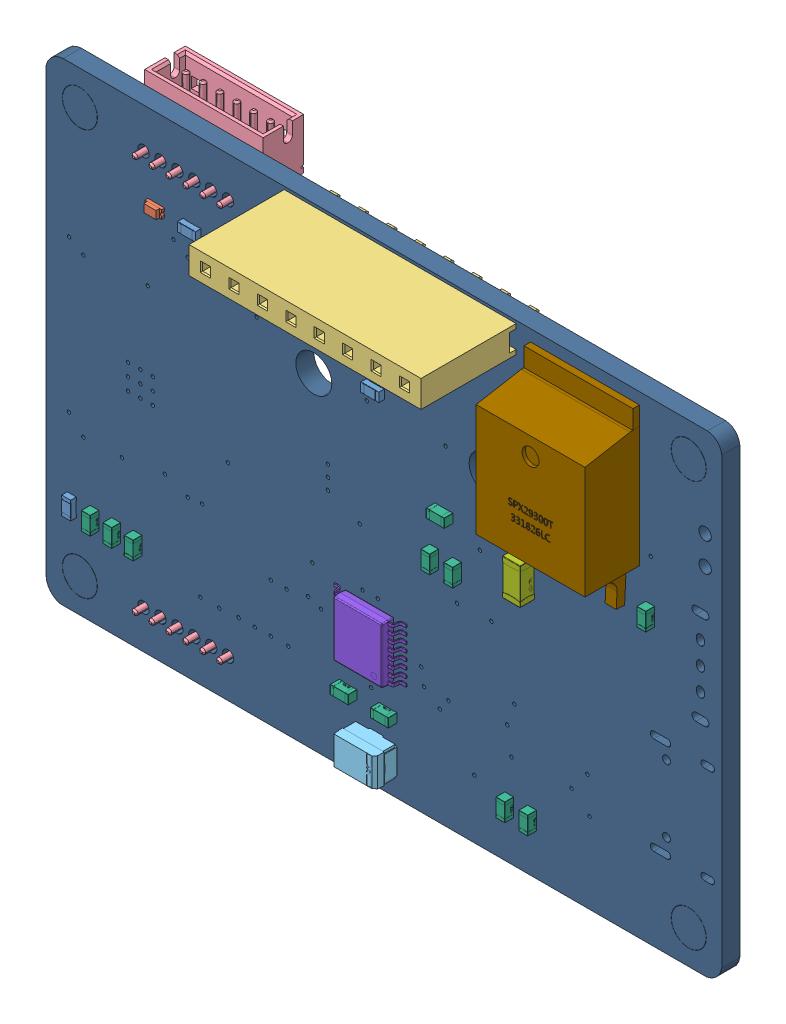
SolidWorks assembly 3D_PCB, configuration 默认. Lengths in mm.
Overall size (59.92 44.49 13.72).
80 component instances, 10 part files, 0 mates.
Components (placement in the parent):
- 3D_PCB.step-1: 3D_PCB.step [默认] at origin size (59.92 44.49 13.72)
  - R1.step-1: R1.step [默认] at (33.7821 35.0521 1.6001) x (-1 0 0) z (0 0 1) size (1.6 0.8 0.51)
    - R0603.step-1: R0603.step [默认] at origin size (1.6 0.8 0.51)
      - COMPOUND.step-1: COMPOUND.step [默认] at origin size (1.6 0.8 0.51)
  - R2.step-1: R2.step [默认] at (29.2101 30.4801 1.6001) size (1.6 0.8 0.51)
    - R0603.step-1: R0603.step [默认] at origin size (1.6 0.8 0.51)
      - COMPOUND.step-1: COMPOUND.step [默认] at origin size (1.6 0.8 0.51)
  - R3.step-1: R3.step [默认] at (23.3409 33.5471 1.6001) size (1.6 0.8 0.51)
    - R0603.step-1: R0603.step [默认] at origin size (1.6 0.8 0.51)
      - COMPOUND.step-1: COMPOUND.step [默认] at origin size (1.6 0.8 0.51)
  - R4.step-1: R4.step [默认] at (23.3409 35.5248 1.6001) size (1.6 0.8 0.51)
    - R0603.step-1: R0603.step [默认] at origin size (1.6 0.8 0.51)
      - COMPOUND.step-1: COMPOUND.step [默认] at origin size (1.6 0.8 0.51)
  - R5.step-1: R5.step [默认] at (12.954 34.6711 1.6001) size (1.6 0.8 0.51)
    - R0603.step-1: R0603.step [默认] at origin size (1.6 0.8 0.51)
      - COMPOUND.step-1: COMPOUND.step [默认] at origin size (1.6 0.8 0.51)
  - R6.step-1: R6.step [默认] at (2.286 8.128 1.6001) x (0 1 0) z (0 0 1) size (1.6 0.8 0.51)
    - R0603.step-1: R0603.step [默认] at origin size (1.6 0.8 0.51)
      - COMPOUND.step-1: COMPOUND.step [默认] at origin size (1.6 0.8 0.51)
  - R7.step-1: R7.step [默认] at (16.129 34.6711 1.6001) x (-1 0 0) z (0 0 1) size (1.6 0.8 0.51)
    - R0603.step-1: R0603.step [默认] at origin size (1.6 0.8 0.51)
      - COMPOUND.step-1: COMPOUND.step [默认] at origin size (1.6 0.8 0.51)
  - LED1.step-1: LED1.step [默认] at (9.779 34.6711 1.6001) size (1.49 0.75 0.56)
    - LED0603-RD_BLUE.step-1: LED0603-RD_BLUE.step [默认] at origin size (1.49 0.75 0.56)
      - COMPOUND-0.step-1: COMPOUND-0.step [默认] at origin size (1.49 0.75 0.56)
  - U6.step-1: U6.step [默认] at (40.3861 40.6401 1.6001) x (0 -1 0) z (0 0 1) size (2.38 20.58 11.62)
    - MPU6050.step-1: MPU6050.step [默认] at origin size (2.38 20.58 11.62)
      - SOLID.step-1: SOLID.step [默认] at origin size (2.38 20.58 11.62)
  - CN1.step-1: CN1.step [默认] at (12.4 3.429 0) x (-1 0 0) z (0 0 -1) size (10.5 4.99 6.1)
    - CONN-TH_ZH1.5-6AW.step-1: CONN-TH_ZH1.5-6AW.step [默认] at origin size (10.5 4.99 6.1)
      - SOLID-1.step-1: SOLID-1.step [默认] at origin size (10.5 4.99 6.1)
  - CN2.step-1: CN2.step [默认] at (12.4 38.4811 0) x (1 0 0) z (0 0 -1) size (10.5 4.99 6.1)
    - CONN-TH_ZH1.5-6AW.step-1: CONN-TH_ZH1.5-6AW.step [默认] at origin size (10.5 4.99 6.1)
      - SOLID-1.step-1: SOLID-1.step [默认] at origin size (10.5 4.99 6.1)
  - U4.step-1: U4.step [默认] at (29.3332 2.8925 1.6001) x (-1 0 0) z (0 0 1) size (3.7 2.6 2)
    - CAP-SMD_L3.5-W2.8-FD.step-1: CAP-SMD_L3.5-W2.8-FD.step [默认] at origin size (3.7 2.6 2)
      - COMPOUND-2.step-1: COMPOUND-2.step [默认] at origin size (3.7 2.6 2)
  - C1.step-1: C1.step [默认] at (41.0883 4.4926 1.6001) x (0 -1 0) z (0 0 1) size (1.6 0.8 0.8)
    - C0603.step-1: C0603.step [默认] at origin size (1.6 0.8 0.8)
      - =_[0_1_1_27].step-1: =_[0_1_1_27].step [默认] at (0 0 0.4) size (1.6 0.8 0.8)
  - C2.step-1: C2.step [默认] at (43.1203 4.4926 1.6001) x (0 -1 0) z (0 0 1) size (1.6 0.8 0.8)
    - C0603.step-1: C0603.step [默认] at origin size (1.6 0.8 0.8)
      - =_[0_1_1_27].step-1: =_[0_1_1_27].step [默认] at (0 0 0.4) size (1.6 0.8 0.8)
  - C3.step-1: C3.step [默认] at (53.5887 25.3846 1.6001) x (0 -1 0) z (0 0 1) size (1.6 0.8 0.8)
    - C0603.step-1: C0603.step [默认] at origin size (1.6 0.8 0.8)
      - =_[0_1_1_27].step-1: =_[0_1_1_27].step [默认] at (0 0 0.4) size (1.6 0.8 0.8)
  - C5.step-1: C5.step [默认] at (34.4275 20.1981 1.6001) x (0 1 0) z (0 0 1) size (1.6 0.8 0.8)
    - C0603.step-1: C0603.step [默认] at origin size (1.6 0.8 0.8)
      - =_[0_1_1_27].step-1: =_[0_1_1_27].step [默认] at (0 0 0.4) size (1.6 0.8 0.8)
  - C6.step-1: C6.step [默认] at (36.4595 20.1981 1.6001) x (0 1 0) z (0 0 1) size (1.6 0.8 0.8)
    - C0603.step-1: C0603.step [默认] at origin size (1.6 0.8 0.8)
      - =_[0_1_1_27].step-1: =_[0_1_1_27].step [默认] at (0 0 0.4) size (1.6 0.8 0.8)
  - C7.step-1: C7.step [默认] at (35.3061 24.003 1.6001) x (-1 0 0) z (0 0 1) size (1.6 0.8 0.8)
    - C0603.step-1: C0603.step [默认] at origin size (1.6 0.8 0.8)
      - =_[0_1_1_27].step-1: =_[0_1_1_27].step [默认] at (0 0 0.4) size (1.6 0.8 0.8)
  - C8.step-1: C8.step [默认] at (8.1226 8.1125 1.6001) x (0 -1 0) z (0 0 1) size (1.6 0.8 0.8)
    - C0603.step-1: C0603.step [默认] at origin size (1.6 0.8 0.8)
      - =_[0_1_1_27].step-1: =_[0_1_1_27].step [默认] at (0 0 0.4) size (1.6 0.8 0.8)
  - C10.step-1: C10.step [默认] at (4.3126 8.1125 1.6001) x (0 -1 0) z (0 0 1) size (1.6 0.8 0.8)
    - C0603.step-1: C0603.step [默认] at origin size (1.6 0.8 0.8)
      - =_[0_1_1_27].step-1: =_[0_1_1_27].step [默认] at (0 0 0.4) size (1.6 0.8 0.8)
  - C9.step-1: C9.step [默认] at (6.223 8.128 1.6001) x (0 -1 0) z (0 0 1) size (1.6 0.8 0.8)
    - C0603.step-1: C0603.step [默认] at origin size (1.6 0.8 0.8)
      - =_[0_1_1_27].step-1: =_[0_1_1_27].step [默认] at (0 0 0.4) size (1.6 0.8 0.8)
  - C12.step-1: C12.step [默认] at (30.3492 6.1945 1.6001) size (1.6 0.8 0.8)
    - C0603.step-1: C0603.step [默认] at origin size (1.6 0.8 0.8)
      - =_[0_1_1_27].step-1: =_[0_1_1_27].step [默认] at (0 0 0.4) size (1.6 0.8 0.8)
  - C11.step-1: C11.step [默认] at (26.7932 6.1945 1.6001) size (1.6 0.8 0.8)
    - C0603.step-1: C0603.step [默认] at origin size (1.6 0.8 0.8)
      - =_[0_1_1_27].step-1: =_[0_1_1_27].step [默认] at (0 0 0.4) size (1.6 0.8 0.8)
  - C4.step-1: C4.step [默认] at (42.5451 22.987 1.6001) x (0 -1 0) z (0 0 1) size (3.2 1.6 1.3)
    - C1206.step-1: C1206.step [默认] at origin size (3.2 1.6 1.3)
      - =_[0_1_1_41].step-1: =_[0_1_1_41].step [默认] at (0 0 0.65) size (3.2 1.6 1.3)
  - U8.step-1: U8.step [默认] at (28.8291 11.43 1.6001) x (0 1 0) z (0 0 1) size (5 6.4 1.2)
    - ETSSOP-16_L5.0-W4.4-P0.65-LS6.4-BL-EP.step-1: ETSSOP-16_L5.0-W4.4-P0.65-LS6.4-BL-EP.step [默认] at origin size (5 6.4 1.2)
      - SOLID-3.step-1: SOLID-3.step [默认] at origin size (5 6.4 1.2)
  - U7.step-1: U7.step [默认] at (48.3871 31.3208 1.6001) x (0 1 0) z (0 0 1) size (16.52 9.65 5.42)
    - TO-263-3_L8.6-W10.2-P2.54-LS14.4-TL.step-1: TO-263-3_L8.6-W10.2-P2.54-LS14.4-TL.step [默认] at origin size (16.52 9.65 5.42)
      - COMPOUND-4.step-1: COMPOUND-4.step [默认] at origin size (16.52 9.65 5.42)
  - COMPOUND-5.step-1: COMPOUND-5.step [默认] at origin size (59.92 42.01 1.6)
